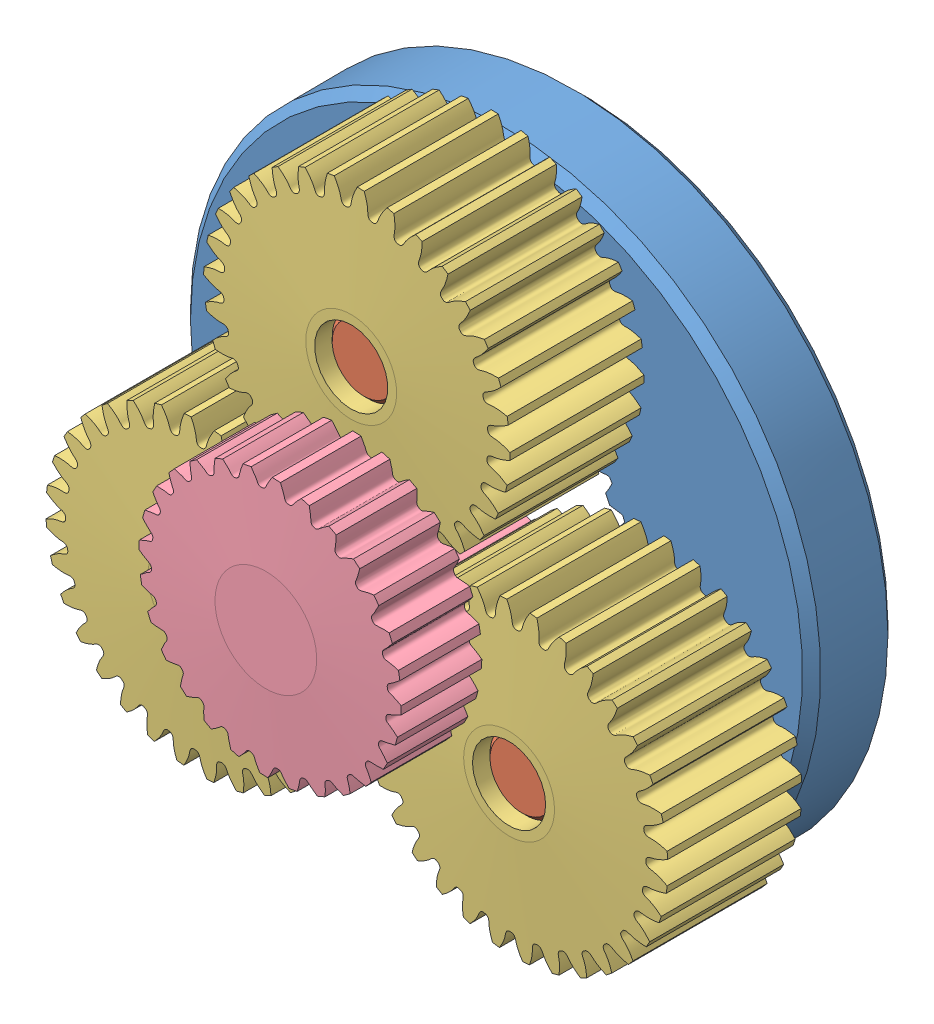
SolidWorks assembly 217-2820 Rev1_Public, configuration Default. Lengths in mm.
Overall size (39.26 38.9 17.4).
9 component instances, 4 part files, 0 mates.
Components (placement in the parent):
- 217-2625-100-1: 217-2625-100 [Default] at origin size (39.26 38.9 12.7)
  - 217-2625-008 Rev1-1: 217-2625-008 Rev1 [Default] at origin size (34.7 34.7 4.7)
  - 217-2625-010 Rev1-1: 217-2625-010 Rev1 [Default] at (0 10.193 3.65) x (0.999813 0.019336 0) z (0 0 1) size (4 4 12)
  - 217-2625-010 Rev1-2: 217-2625-010 Rev1 [Default] at (8.691 -5.3258 3.65) size (4 4 12)
  - 217-2625-010 Rev1-3: 217-2625-010 Rev1 [Default] at (-8.691 -5.3258 3.65) size (4 4 12)
  - 217-2625-005 Rev1_Planet_Revolving_Follower01-1: 217-2625-005 Rev1_Planet_Revolving_Follower01 [Default] at (8.691 -5.3258 6.35) x (0.932816 0.360354 0) z (0 0 1) size (16.91 16.92 8)
  - 217-2625-005 Rev1_Planet_Revolving_Follower01-2: 217-2625-005 Rev1_Planet_Revolving_Follower01 [Default] at (-8.691 -5.3258 6.35) x (-0.932788 -0.360426 0) z (0 0 1) size (16.91 16.92 8)
  - 217-2625-005 Rev1_Planet_Revolving_Follower01-3: 217-2625-005 Rev1_Planet_Revolving_Follower01 [Default] at (0 10.193 6.35) x (0.893583 0.448898 0) z (0 0 1) size (16.91 16.92 8)
- 217-2625-007 Rev1_Public-1: 217-2625-007 Rev1_Public [Default] at (0 0 6.7) x (0.992772 0.120019 0) z (0 0 1) size (14.49 14.49 12.72)
